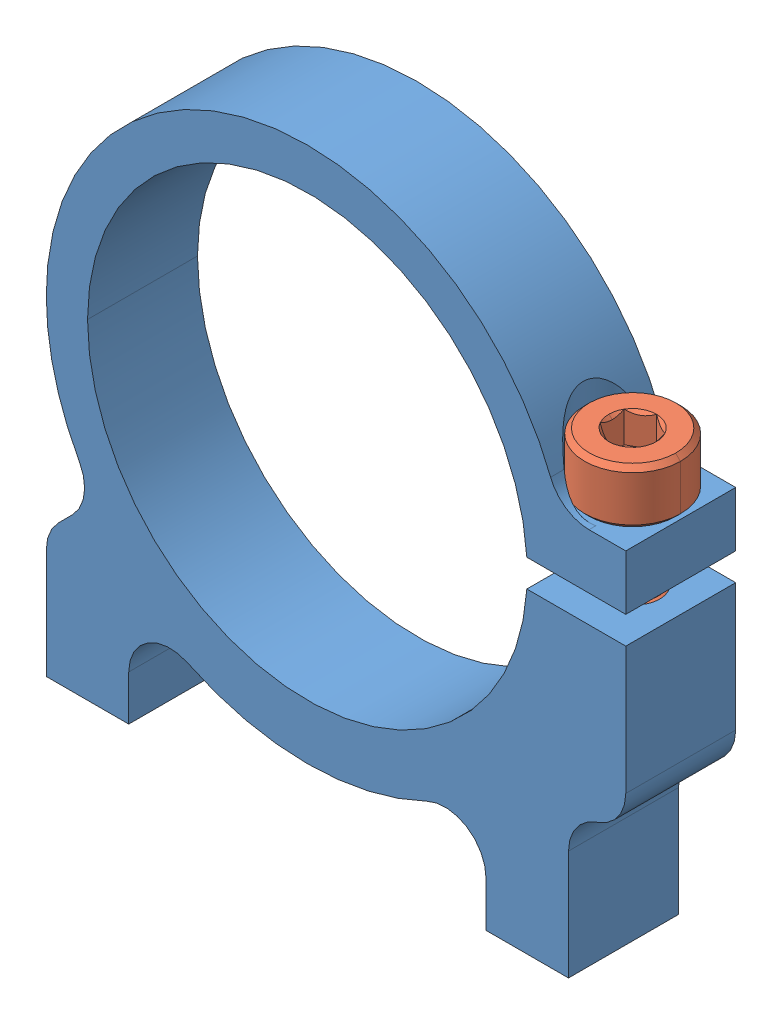
SolidWorks assembly 1400-0032-0032 assembly, configuration Default. Lengths in mm.
Overall size (42.19 43 8).
3 component instances, 2 part files, 0 mates.
Components (placement in the parent):
- 1400-0032-0032 assembly.STEP-1: 1400-0032-0032 assembly.STEP [Default] at origin size (42.19 43 8)
  - 1400-0032-0032.STEP-1: 1400-0032-0032.STEP [Default] at (-9.2052 9.5558 -4.9517) size (42.17 43 8)
  - 2800-0004-0012_90128A207.STEP-1: 2800-0004-0012_90128A207.STEP [Default] at (10.4635 2.5558 -0.9517) x (0.999977 0 0.006769) z (0 -1 0) size (7 7 16.01)
